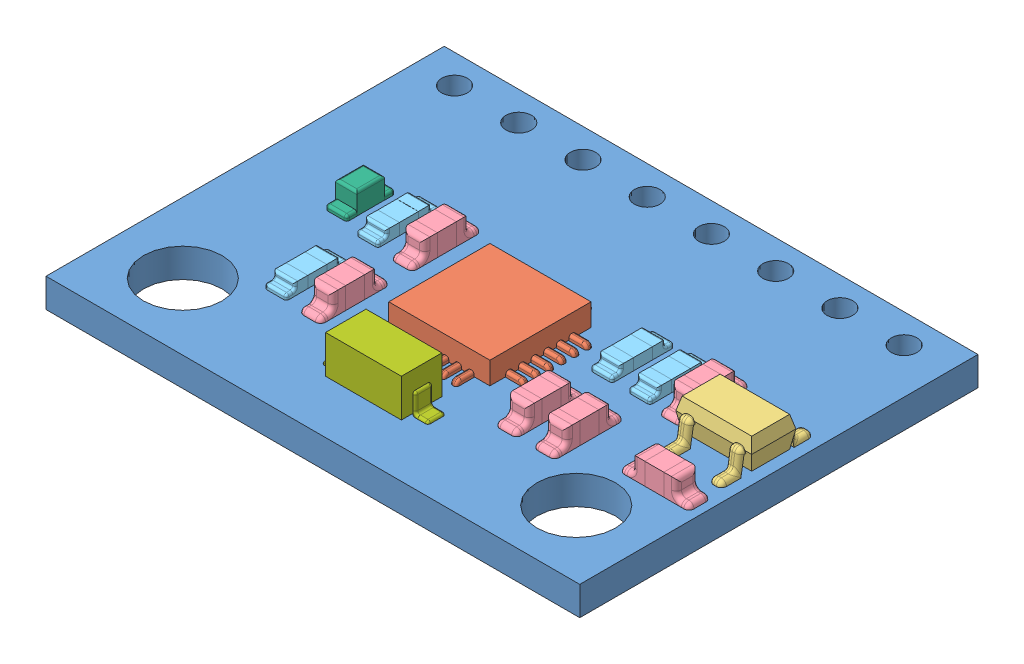
SolidWorks assembly MPU 6050 IMU, configuration Default. Lengths in mm.
Overall size (21.11 2.74 15.75).
23 component instances, 8 part files, 33 mates.
Components (placement in the parent):
- Base-1: Base [Default] at (7.2489 10.9584 16.5726) size (21.11 1.14 15.75)
- pin header-1: pin header [Default] at (16.0246 10.3869 9.8416) x (-1 0 0) z (0 0 1) (suppressed, hidden)
- pin header-2: pin header [Default] at (13.4846 10.3869 9.8416) x (-1 0 0) z (0 0 1) (suppressed, hidden)
- pin header-3: pin header [Default] at (10.9446 10.3869 9.8416) x (-1 0 0) z (0 0 1) (suppressed, hidden)
- pin header-4: pin header [Default] at (8.4046 10.3869 9.8416) x (-1 0 0) z (0 0 1) (suppressed, hidden)
- pin header-5: pin header [Default] at (5.8646 10.3869 9.8416) x (-1 0 0) z (0 0 1) (suppressed, hidden)
- pin header-6: pin header [Default] at (3.3246 10.3869 9.8416) x (-1 0 0) z (0 0 1) (suppressed, hidden)
- pin header-7: pin header [Default] at (0.7846 10.3869 9.8416) x (-1 0 0) z (0 0 1) (suppressed, hidden)
- pin header-8: pin header [Default] at (-1.7554 10.3869 9.8416) x (-1 0 0) z (0 0 1) (suppressed, hidden)
- sensor chip-1: sensor chip [Default] at (7.2489 11.5499 17.4466) size (5.4 0.9 5.4)
- S2NH chip-1: S2NH chip [Default] at (16.1026 12.3799 16.5726) size (3 1.35 3.65)
- Resistor small-3: Resistor small [Default] at (16.1026 11.5314 19.3726) size (2.75 0.99 1)
- Resistor small-4: Resistor small [Default] at (13.9776 11.5314 15.6976) x (0 0 -1) z (1 0 0) size (2.75 0.99 1)
- Resistor small black-3: Resistor small black [Default] at (12.6276 11.5299 15.6976) x (0 0 1) z (-1 0 0) size (2.45 0.6 1.02)
- Resistor small black-4: Resistor small black [Default] at (11.1276 11.5299 15.6976) x (0 0 1) z (-1 0 0) size (2.45 0.6 1.02)
- Resistor small-5: Resistor small [Default] at (12.6276 11.5314 19.3216) x (0 0 -1) z (1 0 0) size (2.75 0.99 1)
- Resistor small-6: Resistor small [Default] at (11.1276 11.5314 19.3216) x (0 0 -1) z (1 0 0) size (2.75 0.99 1)
- Resistor small-7: Resistor small [Default] at (3.3702 11.5314 19.3216) x (0 0 -1) z (1 0 0) size (2.75 0.99 1)
- Resistor small black-5: Resistor small black [Default] at (1.8702 11.5299 15.6972) x (0 0 -1) z (1 0 0) size (2.45 0.6 1.02)
- Resistor small-8: Resistor small [Default] at (3.3702 11.5314 15.6976) x (0 0 1) z (-1 0 0) size (2.75 0.99 1)
- Small LED-1: Small LED [Default] at (0.3652 11.5299 15.6976) size (0.85 0.84 1.9)
- Resistor small black-6: Resistor small black [Default] at (1.8702 11.5299 19.3216) x (0 0 1) z (-1 0 0) size (2.45 0.6 1.02)
- Resistor black-1: Resistor black [Default] at (7.2489 12.3799 21.6466) size (4.2 1.6 1.6)
Mates (geometry in assembly coordinates):
- Concentric1: concentric: cylinder of Base-1 through (16.0246 11.5299 9.8416) axis (0 -1 0) radius 0.508; point of pin header-1
- Coincident4: coincident: plane of Base-1 through (7.2489 10.3869 16.5726) normal (0 -1 0); plane of pin header-1 through (16.0246 10.3869 9.8416) normal (0 1 0)
- Parallel1: parallel: plane of Base-1 through (17.8026 11.5299 24.4466) normal (1 0 0); plane of pin header-1 through (17.2946 7.8469 10.4766) normal (1 0 0)
- Coincident6: coincident: plane of Base-1 through (7.2489 11.5299 16.5726) normal (0 1 0); plane of sensor chip-1 through (7.2489 11.5299 17.4466) normal (0 -1 0)
- Coincident7: coincident: plane of Base-1 through (7.2489 10.9584 16.5726) normal (1 0 0); plane of sensor chip-1 through (7.2489 11.5499 17.4466) normal (1 0 0)
- Distance1: distance = 5 mm: plane of sensor chip-1 through (5.2489 12.4299 19.4466) normal (0 0 1); plane of Base-1 through (-3.3048 11.5299 24.4466) normal (0 0 1)
- Coincident8: coincident: plane of Base-1 through (7.2489 11.5299 16.5726) normal (0 1 0); plane of S2NH chip-1 through (16.1026 11.5299 16.5726) normal (0 -1 0)
- Coincident9: coincident: plane of Base-1 through (7.2489 10.9584 16.5726) normal (0 0 1); plane of S2NH chip-1 through (16.1026 12.3799 16.5726) normal (0 0 1)
- Distance2: distance = 0.2 mm: line of S2NH chip-1 through (17.6026 12.3799 17.4476) axis (0 0 -1); plane of Base-1 through (17.8026 11.5299 24.4466) normal (1 0 0)
- Coincident19: coincident: plane of Base-1 through (7.2489 11.5299 16.5726) normal (0 1 0); plane of Resistor small-3 through (16.9776 11.5299 19.8026) normal (0 -1 0)
- Coincident20: coincident: plane of S2NH chip-1 through (16.1026 12.3799 16.5726) normal (1 0 0); plane of Resistor small-3 through (16.1026 11.5314 19.3726) normal (1 0 0)
- Distance5: distance = 1.5 mm: line of S2NH chip-1 through (15.3258 12.3799 17.4476) axis (1 0 0); plane of Resistor small-3 through (16.4776 11.5314 18.9476) normal (0 0 -1)
- Coincident22: coincident: plane of Base-1 through (7.2489 11.5299 16.5726) normal (0 1 0); plane of Resistor small-4 through (14.4076 11.5299 14.8226) normal (0 -1 0)
- Coincident24: coincident: line of S2NH chip-1 through (16.8794 12.3799 15.6976) axis (-1 0 0); plane of Resistor small-4 through (13.9776 11.5314 15.6976) normal (0 0 -1)
- Distance6: distance = 0.2 mm: plane of Resistor small-4 through (14.4026 11.5314 15.3226) normal (1 0 0); line of S2NH chip-1 through (14.6026 12.3799 15.6976) axis (0 0 1)
- Coincident26: coincident: plane of Base-1 through (7.2489 11.5299 16.5726) normal (0 1 0); plane of Resistor small black-3 through (12.2026 11.5299 16.0726) normal (0 -1 0)
- Coincident28: coincident: plane of Resistor small-4 through (13.9776 11.5314 15.6976) normal (0 0 -1); plane of Resistor small black-3 through (12.6276 11.5299 15.6976) normal (0 0 1)
- Distance7: distance = 0.5 mm: plane of Resistor small-4 through (13.5526 11.5314 15.3226) normal (-1 0 0); plane of Resistor small black-3 through (13.0526 11.5299 16.0726) normal (1 0 0)
- Coincident30: coincident: plane of Base-1 through (7.2489 11.5299 16.5726) normal (0 1 0); plane of Resistor small-5 through (13.0576 11.5299 18.4466) normal (0 -1 0)
- Coincident31: coincident: plane of Resistor small black-3 through (12.6276 11.5299 15.6976) normal (-1 0 0); plane of Resistor small-5 through (12.6276 11.5314 19.3216) normal (1 0 0)
- Distance8: distance = 4.25 mm: plane of Resistor small-5 through (12.6276 11.5314 20.1966) normal (0 0 1); plane of Base-1 through (-3.3048 11.5299 24.4466) normal (0 0 1)
- Coincident33: coincident: plane of Base-1 through (7.2489 11.5299 16.5726) normal (0 1 0); plane of Resistor small-8 through (2.9402 11.5299 14.8226) normal (0 -1 0)
- Coincident34: coincident: plane of Resistor small-7 through (3.3702 11.5314 19.3216) normal (1 0 0); plane of Resistor small-8 through (3.3702 11.5314 15.6976) normal (-1 0 0)
- Coincident36: coincident: line of S2NH chip-1 through (15.8794 12.3799 15.6976) axis (-1 0 0); plane of Resistor small-8 through (3.3702 11.5314 15.6976) normal (0 0 1)
- Coincident37: coincident: plane of Base-1 through (7.2489 11.5299 16.5726) normal (0 1 0); plane of Small LED-1 through (0.3652 11.5299 15.6976) normal (0 -1 0)
- Coincident38: coincident: line of S2NH chip-1 through (15.8794 12.3799 15.6976) axis (-1 0 0); plane of Small LED-1 through (0.3652 11.5299 15.6976) normal (0 0 1)
- Distance9: distance = 1.5 mm: plane of Small LED-1 through (-0.0548 12.3699 16.2476) normal (-1 0 0); plane of Resistor small black-5 through (1.4452 11.5299 15.3222) normal (-1 0 0)
- Coincident40: coincident: plane of Base-1 through (7.2489 11.5299 16.5726) normal (0 1 0); plane of Resistor small black-6 through (1.4452 11.5299 19.6966) normal (0 -1 0)
- Coincident41: coincident: plane of Resistor small black-5 through (1.8702 11.5299 15.6972) normal (1 0 0); plane of Resistor small black-6 through (1.8702 11.5299 19.3216) normal (-1 0 0)
- Coincident42: coincident: plane of Resistor small-7 through (3.3702 11.5314 19.3216) normal (0 0 -1); plane of Resistor small black-6 through (1.8702 11.5299 19.3216) normal (0 0 1)
- Coincident43: coincident: plane of Base-1 through (7.2489 11.5299 16.5726) normal (0 1 0); plane of Resistor black-1 through (5.6489 11.5299 21.9966) normal (0 -1 0)
- Coincident44: coincident: plane of Base-1 through (7.2489 10.9584 16.5726) normal (1 0 0); plane of Resistor black-1 through (7.2489 12.3799 21.6466) normal (1 0 0)
- Distance10: distance = 2 mm: plane of Resistor black-1 through (5.7489 13.1299 22.4466) normal (0 0 1); plane of Base-1 through (-3.3048 11.5299 24.4466) normal (0 0 1)
